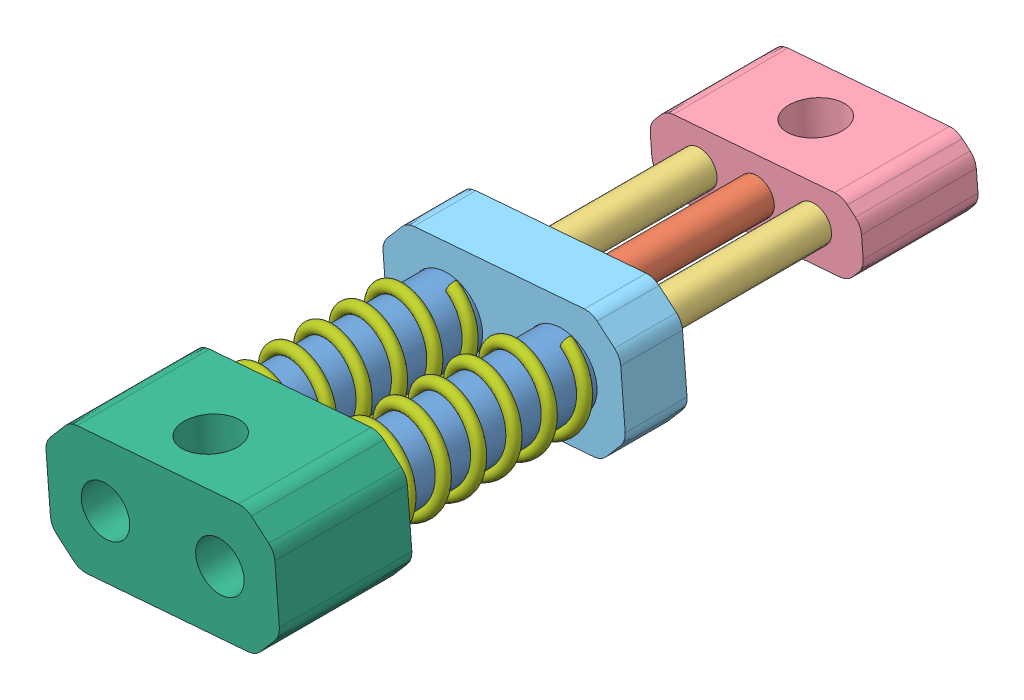
SolidWorks assembly ASS-spring-diag-front_Left, configuration Default. Lengths in mm.
Overall size (28.65 16.73 80.26).
11 component instances, 7 part files, 16 mates.
Components (placement in the parent):
- POM-D8-L34-1: POM-D8-L34 [Défaut] at (1.7738 -1.0277 0) size (8 8 34)
- AL-D4-L29-front-1: AL-D4-L29-front [Default] at (-4.7055 -1.5468 -28.9085) x (-0.97442 -0.224732 0) z (0.224732 -0.97442 0) size (4 30.5 4)
- POM-D8-L34-2: POM-D8-L34 [Défaut] at (-11.1847 -2.066 0) x (0.926019 -0.377477 0) z (0 0 1) size (8 8 34)
- Assem1^ASS-spring-diag-front-1: Assem1^ASS-spring-diag-front [Default] at (-4.7055 -1.5468 -38.2585) x (-0.996805 -0.079868 0) z (-0.079868 0.996805 0) size (24 68 8)
  - AL-D4-L50-front-5: AL-D4-L50-front [Default] at (-6.5 20.5 0) x (0.97074 0 -0.240131) z (-0.240131 0 -0.97074) size (4 65 4)
  - AL-D4-L50-front-4: AL-D4-L50-front [Default] at (6.5 20.5 0) x (0 0 -1) z (-1 0 0) size (4 65 4)
  - POM-cube-l2-upper-1: POM-cube-l2-upper [Default] at (0 -8.5 0) size (24 13 8)
- double-slider-1: double-slider [Default] at (-4.7055 -1.5468 -11.6585) x (0 0 -1) z (-0.996805 -0.079868 0) size (7 14 27)
- POM-cube-l2-lower-1: POM-cube-l2-lower [Default] at (-4.7055 -1.5468 19.5) x (0.996805 0.079868 0) z (-0.079868 0.996805 0) size (26 15 14)
- Spring_RDF-1799-1: Spring_RDF-1799 [Défaut] at (1.7738 -1.0277 12) x (-0.923728 -0.383049 0) z (0 0 -1) size (12.01 12.01 25.3)
- Spring_RDF-1799-2: Spring_RDF-1799 [Défaut] at (-11.1847 -2.066 12) x (-0.923728 -0.383049 0) z (0 0 -1) size (12.01 12.01 25.3)
Mates (geometry in assembly coordinates):
- Concentric97: concentric anti-aligned: cylinder of POM-D8-L34-1 through (1.7738 -1.0277 17) axis (0 0 -1) radius 4; cylinder of Assem1^ASS-spring-diag-front-1/AL-D4-L50-front-5 through (1.7738 -1.0277 -17.7585) axis (0 0 1) radius 2
- Coincident99: coincident anti-aligned: plane of double-slider-1 through (-4.7055 -1.5468 -13.6585) normal (0 0 -1); plane of AL-D4-L29-front-1 through (-4.7055 -1.5468 -13.6585) normal (0 0 1)
- Concentric101: concentric anti-aligned: cylinder of POM-D8-L34-2 through (-11.1847 -2.066 17) axis (0 0 -1) radius 4; cylinder of double-slider-1 through (-11.1847 -2.066 -18.6585) axis (0 0 1) radius 4.05
- Coincident344: coincident anti-aligned: plane of POM-cube-l2-lower-1 through (1.7738 -1.0277 17) normal (0 0 -1); plane of POM-D8-L34-1 through (1.7738 -1.0277 17) normal (0 0 1)
- Concentric163: concentric aligned: cylinder of POM-cube-l2-lower-1 through (1.7738 -1.0277 17) axis (0 0 -1) radius 4; cylinder of POM-D8-L34-1 through (1.7738 -1.0277 17) axis (0 0 -1) radius 4
- Concentric164: concentric aligned: cylinder of POM-cube-l2-lower-1 through (-11.1847 -2.066 17) axis (0 0 -1) radius 4; cylinder of POM-D8-L34-2 through (-11.1847 -2.066 17) axis (0 0 -1) radius 4
- Coincident345: coincident anti-aligned: plane of POM-cube-l2-lower-1 through (-11.1847 -2.066 17) normal (0 0 -1); plane of POM-D8-L34-2 through (-11.1847 -2.066 17) normal (0 0 1)
- Concentric165: concentric anti-aligned: cylinder of POM-D8-L34-2 through (-11.1847 -2.066 17) axis (0 0 -1) radius 4; cylinder of Assem1^ASS-spring-diag-front-1/AL-D4-L50-front-4 through (-11.1847 -2.066 -17.7585) axis (0 0 1) radius 2
- Concentric166: concentric anti-aligned: cylinder of AL-D4-L29-front-1 through (-4.7055 -1.5468 -28.9085) axis (0 0 1) radius 2; cylinder of double-slider-1 through (-4.7055 -1.5468 -13.6585) axis (0 0 -1) radius 2.1
- Coincident346: coincident anti-aligned: plane of AL-D4-L29-front-1 through (-4.7055 -1.5468 -44.1585) normal (0 0 -1); plane of Assem1^ASS-spring-diag-front-1/POM-cube-l2-upper-1 through (-4.7055 -1.5468 -44.1585) normal (0 0 1)
- Coaxiale1: concentric anti-aligned: cylinder of POM-D8-L34-1 through (1.7738 -1.0277 17) axis (0 0 -1) radius 4; cylinder of double-slider-1 through (1.7738 -1.0277 -18.6585) axis (0 0 1) radius 4.05
- Coïncidente1: coincident aligned: plane of POM-cube-l2-lower-1 through (8.8121 -7.4862 12) normal (0 0 -1); plane of Spring_RDF-1799-1 through (1.7738 -1.0277 12) normal (0 0 -1)
- Coaxiale2: concentric aligned: cylinder of POM-D8-L34-1 through (1.7738 -1.0277 17) axis (0 0 -1) radius 4; line of Spring_RDF-1799-1 through (1.7738 -1.0277 12) axis (0 0 -1)
- Coïncidente3: coincident aligned: plane of POM-cube-l2-lower-1 through (8.8121 -7.4862 12) normal (0 0 -1); plane of Spring_RDF-1799-2 through (-11.1847 -2.066 12) normal (0 0 -1)
- Coaxiale3: concentric aligned: cylinder of POM-D8-L34-2 through (-11.1847 -2.066 17) axis (0 0 -1) radius 4; line of Spring_RDF-1799-2 through (-11.1847 -2.066 12) axis (0 0 -1)
- Distance2: distance = 10 mm anti-aligned: plane of POM-cube-l2-lower-1 through (8.7522 -6.7386 12) normal (0 0 -1); plane of double-slider-1 through (-17.6033 -9.6027 2) normal (0 0 1)
